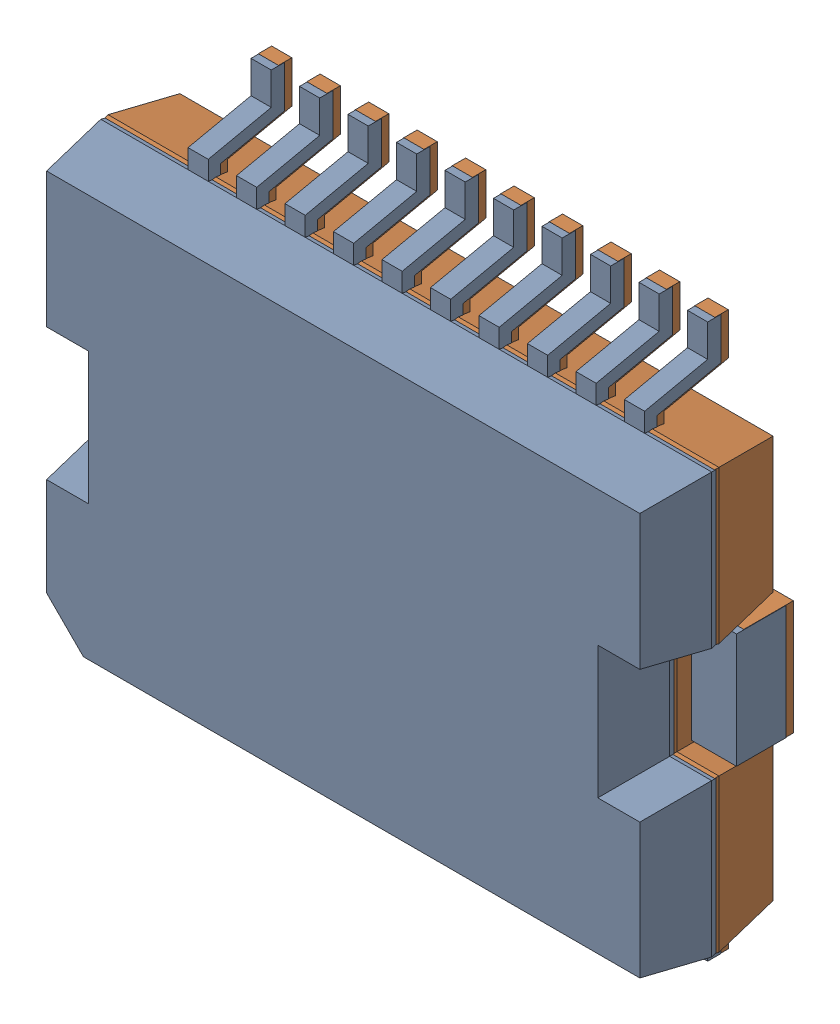
SolidWorks assembly L6234, configuration Default. Lengths in mm.
Overall size (16.01 14.5 3.85).
2 component instances, 1 part files, 0 mates.
Components (placement in the parent):
- L6234PD-1: L6234PD [Default] at (20.7048 33.6248 0.2) x (1 0 0) z (0 -1 0) size (16 3.65 14.5)
- L6234PD-2: L6234PD [Default] at (20.6947 33.6248 0) x (1 0 0) z (0 -1 0) size (16 3.65 14.5)
